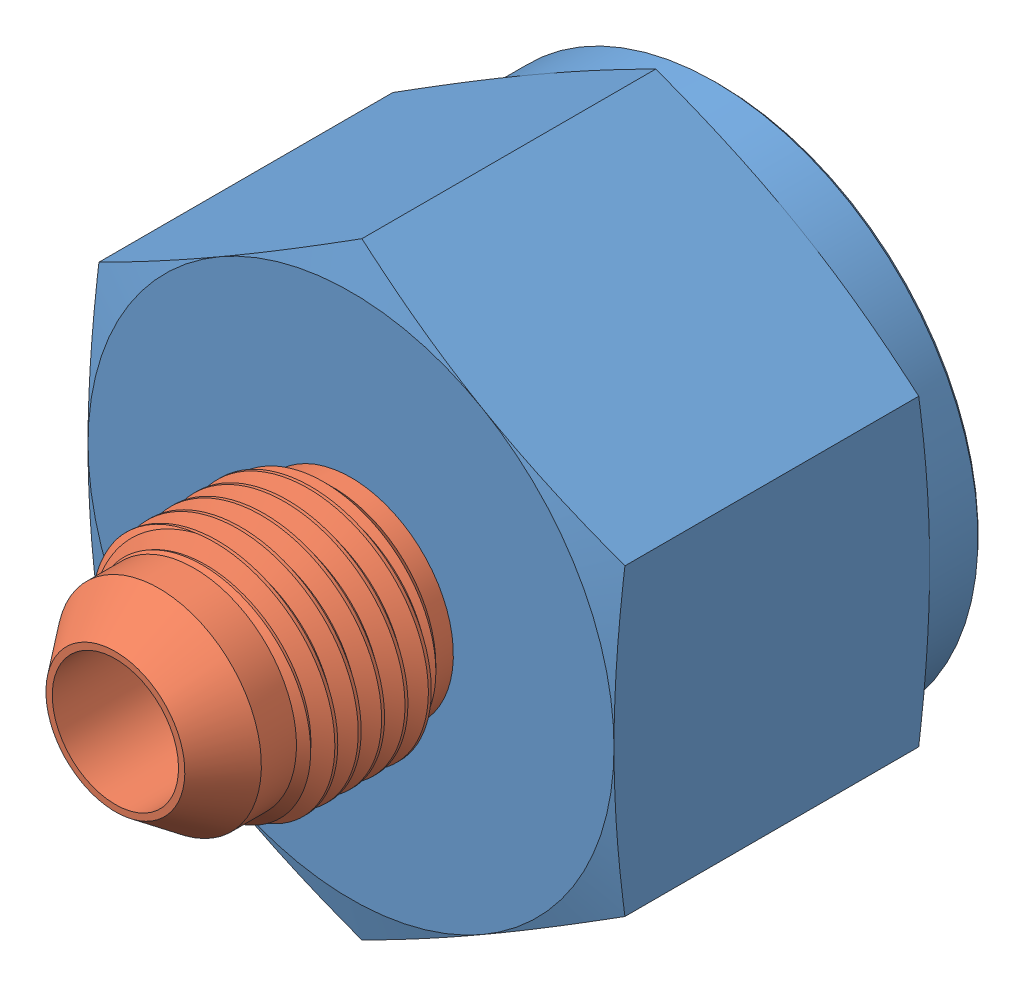
SolidWorks assembly -12FAN -6AN, configuration Default. Lengths in mm.
Overall size (31.75 36.66 37.28).
2 component instances, 2 part files, 2 mates.
Components (placement in the parent):
- -12FAN Al half-1: -12FAN Al half [2227K64] at (-3.2944 22.4941 19.305) size (31.75 36.66 23.05)
- -6AN Half-1: -6AN Half [50715K174] at (-3.2944 22.4941 37.847) x (0 0 -1) z (0.89869 0.438585 0) size (14.22 14.98 14.55)
Mates (geometry in assembly coordinates):
- Concentric3: concentric anti-aligned: cylinder of -12FAN Al half-1 through (-3.2944 22.4941 19.305) axis (0 0 1) radius 5.9264; cylinder of -6AN Half-1 through (-3.2944 22.4941 19.94) axis (0 0 -1) radius 3.81
- Coincident2: coincident anti-aligned: plane of -12FAN Al half-1 through (-22.3444 3.8258 41.53) normal (0 0 1); plane of -6AN Half-1 through (-8.1986 3.5864 41.53) normal (0 0 -1)
